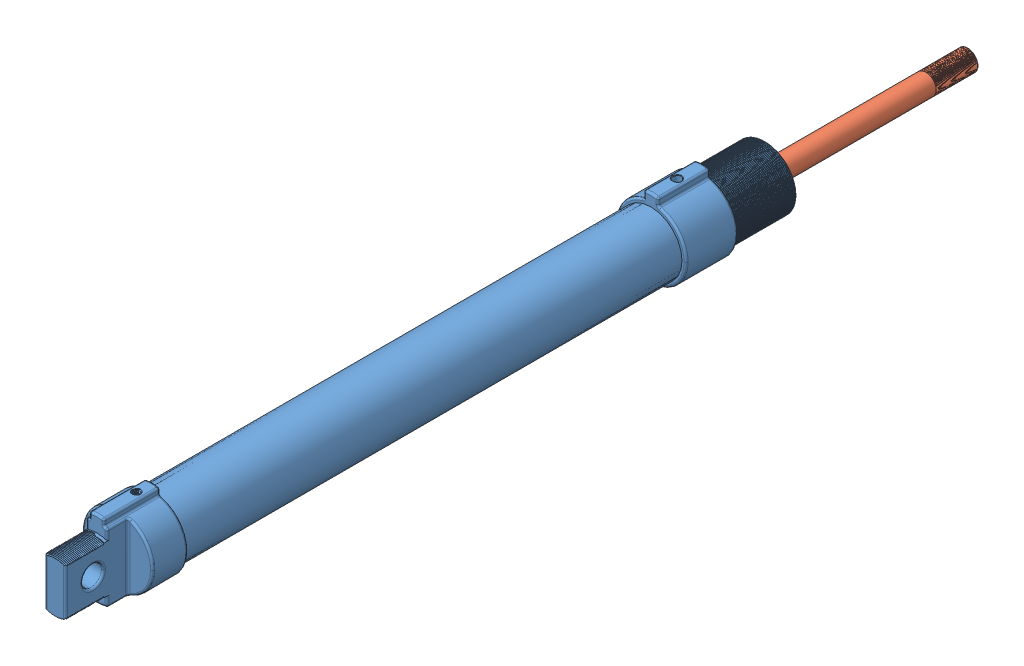
SolidWorks assembly piston-rod, configuration Default. Lengths in mm.
Overall size (41.46 47.99 440.27).
2 component instances, 2 part files, 2 mates.
Components (placement in the parent):
- cylender-1: cylender [Default] at (36.6911 203.0781 180.4291) size (40.07 46.79 343.61)
- rod-1: rod [Default] at (36.6911 203.0781 327.8454) x (0.711096 -0.703095 0) z (0 0 -1) size (26 26 337)
Mates (geometry in assembly coordinates):
- Concentric1: concentric aligned: cylinder of cylender-1 through (36.6911 203.0781 180.4291) axis (0 0 1) radius 15; cylinder of rod-1 through (36.6911 203.0781 47.8454) axis (0 0 1) radius 5
- LimitDistance1: limit distance = 55.5838 mm anti-aligned: plane of rod-1 through (36.6911 203.0781 364.8454) normal (0 0 1); plane of cylender-1 through (20.4991 186.8672 420.4291) normal (0 0 -1)
